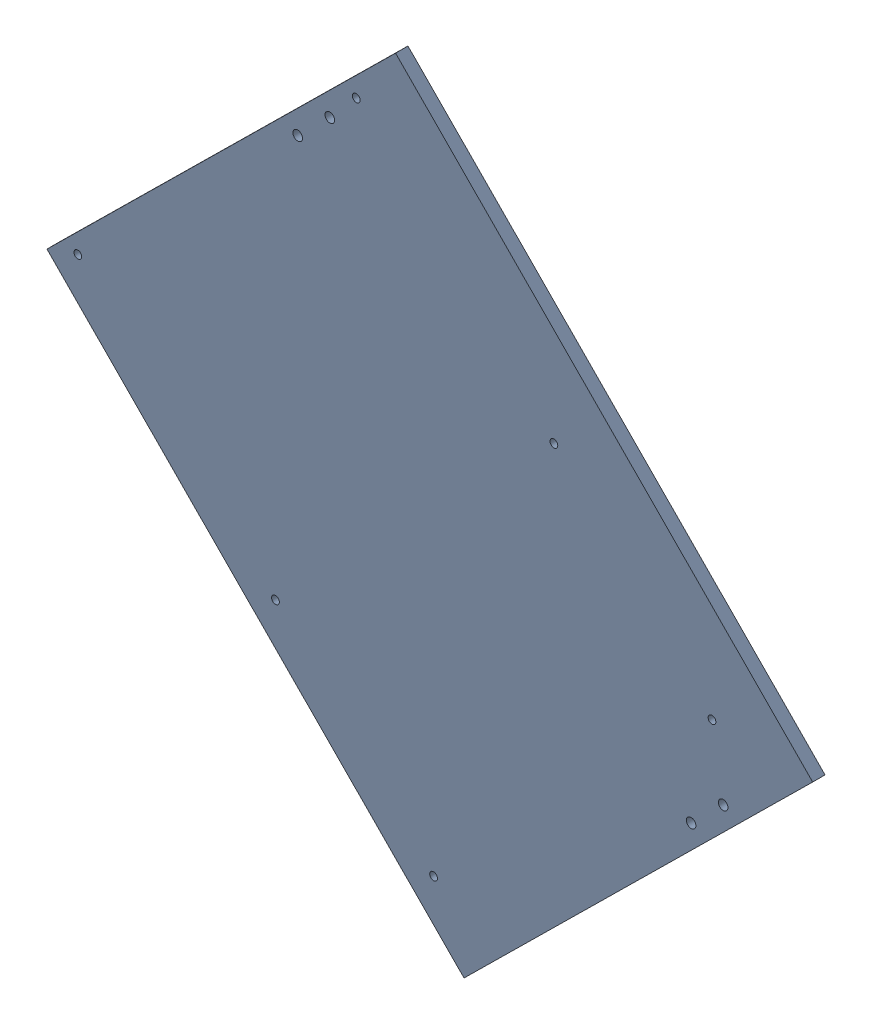
SolidWorks assembly Glassbed Assembly, configuration Default. Lengths in mm.
Overall size (272.13 272.48 4.4).
5 component instances, 2 part files, 1 mates.
Components (placement in the parent):
- Magnet (12x3.79mm)-1: Magnet (12x3.79mm) [Default] at origin (suppressed, hidden)
- Magnet (12x3.79mm)-2: Magnet (12x3.79mm) [Default] at (-88.7992 94.8712 0) x (0.188675 -0.98204 0) z (0 0 1) (suppressed, hidden)
- Magnet (12x3.79mm)-3: Magnet (12x3.79mm) [Default] at (81.2456 127.0743 0) x (-0.057101 -0.998368 0) z (0 0 1) (suppressed, hidden)
- Magnet (12x3.79mm)-4: Magnet (12x3.79mm) [Default] at (10.1427 192.5007 0) x (0.188675 -0.98204 0) z (0 0 1) (suppressed, hidden)
- Glassbed2-1: Glassbed2 [Default] at (-254.8233 439.0509 3.79) x (0.711812 0.70237 0) z (0 0 1) size (174.06 211.05 4.4)
Mates (geometry in assembly coordinates):
- Coincident25: coincident: plane of assembly; plane of Magnet (12x3.79mm)-1 through (5.0563 23.079 3.79) normal (0 0 1); plane of Glassbed2-1 through (-254.8233 439.0509 3.79) normal (0 0 -1)
